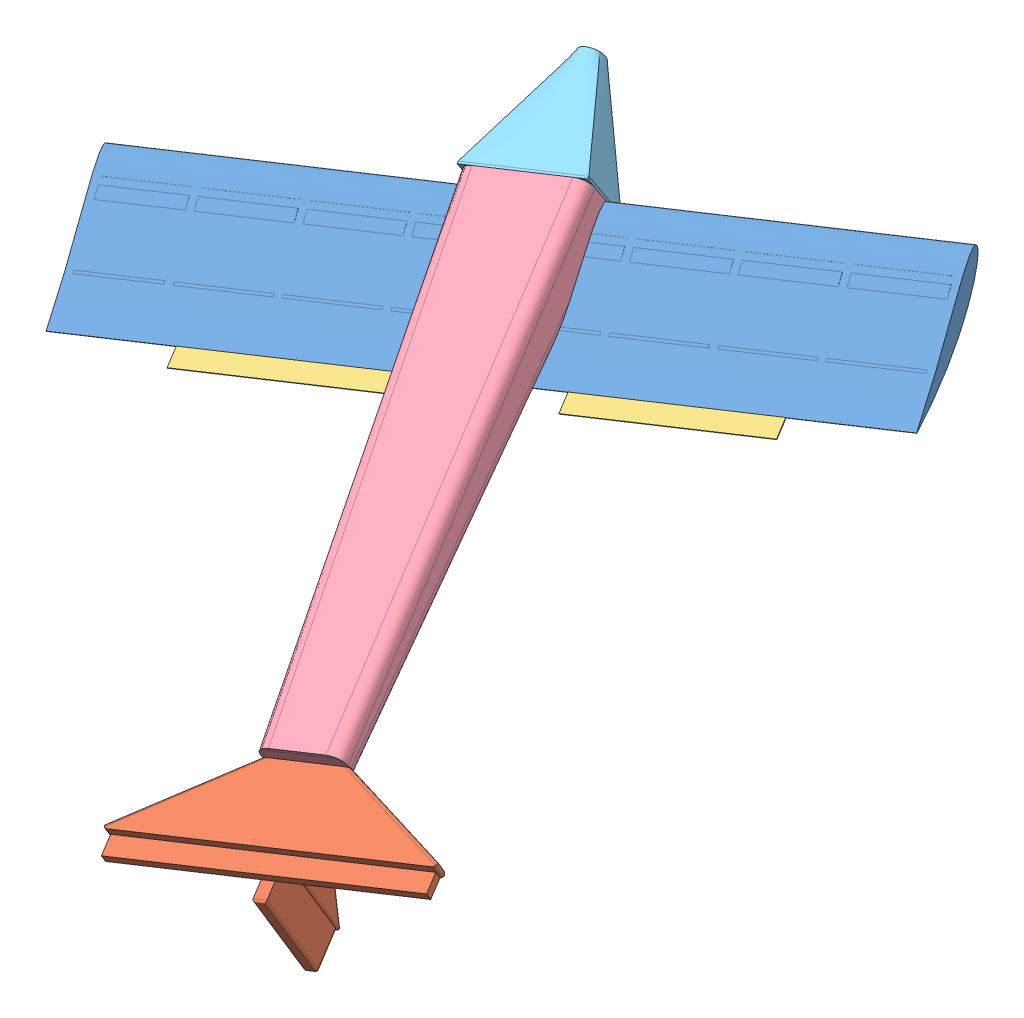
SolidWorks assembly Plane, configuration Default. Lengths in mm.
Overall size (1009.49 663.96 867.98).
6 component instances, 5 part files, 20 mates.
Components (placement in the parent):
- Naca 4512 airfoil-1: Naca 4512 airfoil [Default] at (1289.4297 815.0448 -525.1265) x (0.335632 -0.575694 0.745606) z (0.941703 0.224684 -0.250423) size (200.15 25.92 1000)
- Tail-1: Tail [Default] at (1430.0821 559.0271 -36.1653) x (0.941703 0.224684 -0.250423) z (-0.327729 0.44428 -0.833792) size (381.58 148.05 150)
- Ailron-1: Ailron [Default] at (1668.4229 821.535 -501.663) x (-0.941703 -0.224684 0.250423) z (0.327729 -0.44428 0.833792) size (250 1 25)
- Ailron-2: Ailron [Default] at (1001.0373 675.3633 -347.2116) x (0.941703 0.224684 -0.250423) z (-0.327729 0.44428 -0.833792) size (250 1 25)
- fuselage-1: fuselage [Default] at (1263.1541 873.7248 -581.1957) x (0.941703 0.224684 -0.250423) z (0.060891 -0.84585 -0.529934) size (150 650 75)
- nose plane-1: nose plane [Default] at (1262.1615 875.1762 -583.6264) x (-0.941703 -0.224684 0.250423) z (-0.330888 0.483792 -0.810221) size (150 75 153.01)
Mates (geometry in assembly coordinates):
- Parallel1: parallel: line of Naca 4512 airfoil-1 through (1801.523 865.9144 -560.3154) axis (-0.941703 -0.224684 0.250423); plane of Ailron-1 through (1668.499 820.6677 -502.1551) normal (0.327729 -0.44428 0.833792)
- Coincident2: coincident anti-aligned: plane of Naca 4512 airfoil-1 through (1801.523 865.9144 -560.3154) normal (0.327729 -0.44428 0.833792); plane of Ailron-1 through (1660.3058 831.7747 -522.9999) normal (-0.327729 0.44428 -0.833792)
- Parallel2: parallel anti-aligned: line of Naca 4512 airfoil-1 through (1801.523 865.9144 -560.3154) axis (0.076082 -0.867256 -0.492015); line of Ailron-1 through (1660.3058 831.7747 -522.9999) axis (-0.076082 0.867256 0.492015)
- Coincident4: coincident anti-aligned: line of Naca 4512 airfoil-1 through (1801.5613 865.4773 -560.5633) axis (-0.941703 -0.224684 0.250423); line of Ailron-1 through (1424.8799 775.6038 -460.394) axis (0.941703 0.224684 -0.250423)
- Distance1: distance = 150 mm aligned: plane of Ailron-1 through (1668.499 820.6677 -502.1551) normal (0.941703 0.224684 -0.250423); plane of Naca 4512 airfoil-1 through (1734.6648 978.5482 -710.6752) normal (0.941703 0.224684 -0.250423)
- Coincident6: coincident anti-aligned: line of Naca 4512 airfoil-1 through (1801.5613 865.4773 -560.5633) axis (-0.941703 -0.224684 0.250423); line of Ailron-2 through (1001.1134 674.4961 -347.7036) axis (0.941703 0.224684 -0.250423)
- Coincident7: coincident anti-aligned: plane of Naca 4512 airfoil-1 through (1801.523 865.9144 -560.3154) normal (0.327729 -0.44428 0.833792); plane of Ailron-2 through (1001.1134 674.4961 -347.7036) normal (-0.327729 0.44428 -0.833792)
- Distance2: distance = 150 mm: line of Ailron-2 through (1001.1134 674.4961 -347.7036) axis (-0.076082 0.867256 0.492015); line of Naca 4512 airfoil-1 through (859.8195 641.2305 -309.8922) axis (0.076082 -0.867256 -0.492015)
- Parallel5: parallel anti-aligned: plane of Tail-1 through (1430.0821 559.0271 -36.1653) normal (-0.076082 0.867256 0.492015); plane of fuselage-1 through (1194.8098 825.1541 -582.2865) normal (0.076082 -0.867256 -0.492015)
- Coincident11: coincident aligned: plane of Tail-1 through (1431.6037 541.6819 -46.0056) normal (0.076082 -0.867256 -0.492015); plane of fuselage-1 through (1194.8098 825.1541 -582.2865) normal (0.076082 -0.867256 -0.492015)
- Coincident16: coincident aligned: line of Tail-1 through (1438.3945 543.3022 -47.8114) axis (0.941703 0.224684 -0.250423); line of fuselage-1 through (1447.5953 545.4974 -50.2582) axis (0.941703 0.224684 -0.250423)
- Distance3: distance = 25 mm: point of Tail-1; line of fuselage-1 through (1447.5953 545.4974 -50.2582) axis (-0.363641 0.435326 -0.823563)
- Distance4: distance = 425 mm: plane of Naca 4512 airfoil-1 through (1734.6648 978.5482 -710.6752) normal (0.941703 0.224684 -0.250423); line of fuselage-1 through (1335.0309 873.2259 -610.8475) axis (-0.060891 0.84585 0.529934)
- Parallel17: parallel anti-aligned: line of Ailron-1 through (1668.499 820.6677 -502.1551) axis (-0.941703 -0.224684 0.250423); line of fuselage-1 through (1210.8022 828.9698 -586.5393) axis (0.941703 0.224684 -0.250423)
- Parallel18: parallel anti-aligned: plane of Ailron-2 through (1001.0373 675.3633 -347.2116) normal (-0.076082 0.867256 0.492015); plane of fuselage-1 through (1194.8098 825.1541 -582.2865) normal (0.076082 -0.867256 -0.492015)
- Coincident26: coincident: line of Naca 4512 airfoil-1 through (1801.523 865.9144 -560.3154) axis (-0.941703 -0.224684 0.250423); plane of fuselage-1 through (1194.8098 825.1541 -582.2865) normal (0.076082 -0.867256 -0.492015)
- Tangent3: tangent: curve of Naca 4512 airfoil-1; plane of fuselage-1 through (1263.1541 873.7248 -581.1957) normal (-0.330888 0.483792 -0.810221)
- Coincident36: coincident aligned: line of fuselage-1 through (1315.4824 918.4741 -575.8458) axis (-0.941703 -0.224684 0.250423); line of nose plane-1 through (1331.4985 922.2954 -580.1049) axis (-0.941703 -0.224684 0.250423)
- Coincident37: coincident anti-aligned: plane of fuselage-1 through (1263.1541 873.7248 -581.1957) normal (-0.330888 0.483792 -0.810221); plane of nose plane-1 through (1263.1541 873.7248 -581.1957) normal (0.330888 -0.483792 0.810221)
- Coincident38: coincident: line of fuselage-1 through (1335.0309 873.2259 -610.8475) axis (-0.060891 0.84585 0.529934); plane of nose plane-1 through (1336.0653 858.8567 -619.85) normal (0.941703 0.224684 -0.250423)
